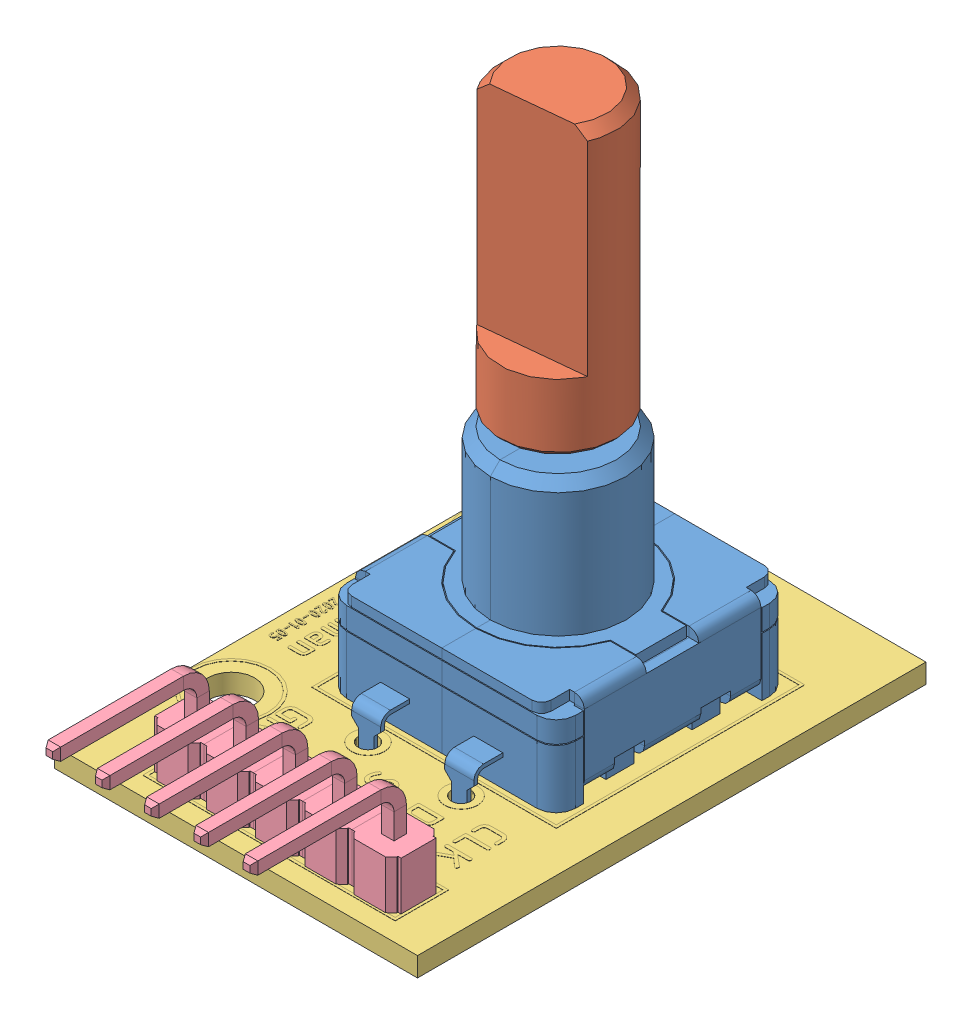
SolidWorks assembly KY-040 Rotary Encoder, configuration Default. Lengths in mm.
Overall size (18.7 30.1 31.47).
4 component instances, 4 part files, 8 mates.
Components (placement in the parent):
- Rotary Encoder-1: Rotary Encoder [Default] at (5.1929 2.265 12.688) size (11.8 14.9 15)
- D-handle-1: D-handle [Default] at (5.1929 8.865 12.688) x (-0.994918 0 0.100689) z (-0.100689 0 -0.994918) size (6 20.2 6)
- pcb-1: pcb [Default] at (-5.1071 1.765 2.138) x (0 0 1) z (-1 0 0) size (26.2 1.02 18.7)
- 2.54 5PIN 90-1: 2.54 5PIN 90 [Default] at (-0.1071 2.265 26.008) x (-1 0 0) z (0 0 -1) size (12.7 7.32 8.85)
Mates (geometry in assembly coordinates):
- 同心1: concentric anti-aligned: cylinder of Rotary Encoder-1 through (5.1929 8.865 12.688) axis (0 1 0) radius 1.425; cylinder of D-handle-1 through (5.1929 14.565 12.688) axis (0 -1 0) radius 1.3
- 重合2: coincident anti-aligned: plane of Rotary Encoder-1 through (5.1929 8.865 12.688) normal (0 1 0); plane of D-handle-1 through (5.1929 8.865 12.688) normal (0 -1 0)
- 距离2: distance = 4.4 mm aligned: plane of pcb-1 through (-5.1071 1.265 2.138) normal (-1 0 0); plane of Rotary Encoder-1 through (-0.7071 2.265 12.688) normal (-1 0 0)
- 重合4: coincident anti-aligned: plane of Rotary Encoder-1 through (10.0929 2.265 17.688) normal (0 -1 0); plane of pcb-1 through (-5.1071 2.265 2.138) normal (0 1 0)
- 距离3: distance = 4.55 mm aligned: plane of Rotary Encoder-1 through (0.2929 5.265 6.688) normal (0 0 -1); plane of pcb-1 through (-5.1071 1.265 2.138) normal (0 0 -1)
- 距离4: distance = 0.77 mm aligned: plane of 2.54 5PIN 90-1 through (11.1529 4.765 27.258) normal (0 0 1); cylinder of pcb-1 through (10.0529 1.265 25.988) axis (0 -1 0) radius 0.5
- 重合6: coincident anti-aligned: plane of pcb-1 through (-5.1071 2.265 2.138) normal (0 1 0); plane of 2.54 5PIN 90-1 through (10.0529 2.265 26.008) normal (0 -1 0)
- 距离5: distance = 1.27 mm: plane of 2.54 5PIN 90-1 through (11.3229 4.765 25.108) normal (1 0 0); cylinder of pcb-1 through (10.0529 1.265 25.988) axis (0 -1 0) radius 0.5
